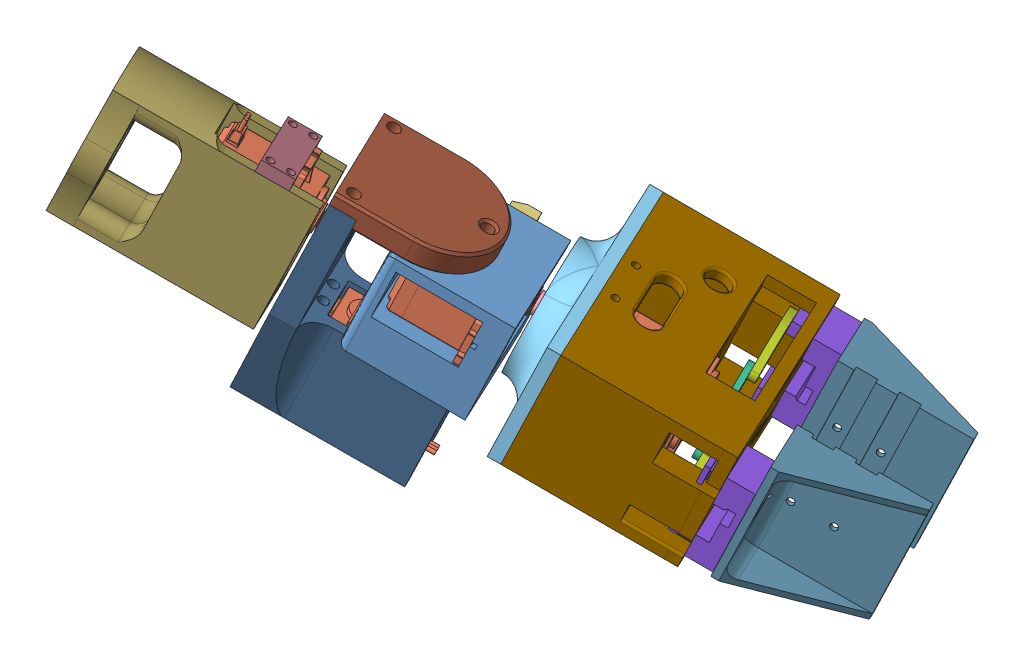
SolidWorks assembly Assem1_Arm_V2, configuration Default. Lengths in mm.
Overall size (291.27 151.15 200.95).
25 component instances, 16 part files, 64 mates.
Components (placement in the parent):
- Gripper_Servo_Case_01-1: Gripper_Servo_Case_01 [Default] at (637.8527 1736.4964 358.4688) x (-0.339499 -0.919036 0.200284) z (0.832449 -0.392704 -0.390912) size (42 54.23 47.25)
- servoMotorMG996R-1: servoMotorMG996R [Default] at (649.6883 1708.0671 323.7215) x (-0.437915 -0.034012 -0.898373) z (-0.339499 -0.919036 0.200284) size (56.95 44.55 19.7)
- Gripper_Case_Cover-1: Gripper_Case_Cover [Default] at (642.9248 1721.1114 296.4702) x (-0.339499 -0.919036 0.200284) z (0.832449 -0.392704 -0.390912) size (30 10 10)
- servoMotorMG996R_Part_Connection_02-3: servoMotorMG996R_Part_Connection_02 [Default] at (660.7487 1700.4192 307.3765) x (-0.339908 -0.919067 0.199444) z (-0.437597 -0.033153 -0.89856) size (20.7 5.75 20.7)
- Base-1: Base [Default] at (676.3768 1700.3789 299.7672) x (0.437597 0.033153 0.89856) z (-0.339908 -0.919067 0.199444) size (100 16.72 50)
- servoMotorMG996R-3: servoMotorMG996R [Default] at (703.1283 1682.8468 298.6268) x (-0.437597 -0.033153 -0.89856) z (-0.339908 -0.919067 0.199444) size (56.95 44.55 19.7)
- Steel_Bar_01-1: Steel_Bar_01 [Default] at (778.4176 1569.0185 297.1188) x (-0.8415 0.403515 0.359239) z (-0.523541 -0.444939 -0.726591) size (40 200 40) (hidden)
- servoMotorMG996R_Part_Connection_04-1: servoMotorMG996R_Part_Connection_04 [Default] at (714.1921 1675.2077 282.2804) x (0.530416 0.768818 0.35718) z (0.160274 -0.50468 0.848298) size (12.1 5.75 37.4)
- Part4-1: Part4 [Default] at (707.8264 1685.09 258.7968) x (-0.312756 0.249358 -0.916517) z (0.832449 -0.392704 -0.390912) size (31.74 9.94 3)
- Part4-3: Part4 [Default] at (724.4217 1663.1396 308.5134) x (-0.326632 0.222103 -0.918685) z (-0.832449 0.392704 0.390912) size (31.74 9.94 3)
- Part3-1: Part3 [Default] at (712.8244 1667.3969 230.1682) x (-0.339908 -0.919067 0.199444) z (0.437597 0.033153 0.89856) size (35.5 19.25 20)
- Part3-2: Part3 [Default] at (752.6871 1665.5038 316.9578) x (0.339908 0.919067 -0.199444) z (-0.437597 -0.033153 -0.89856) size (35.5 19.25 20)
- Rack_Pinion_Base-1: Rack_Pinion_Base [Default] at (693.6373 1645.9394 237.7253) x (0.437597 0.033153 0.89856) z (-0.832449 0.392704 0.390912) size (100 50 65.35)
- servoMotorMG996R-6: servoMotorMG996R [Default] at (617.9256 1679.4163 340.3753) x (0.829062 -0.392954 -0.397799) z (0.444294 0.030996 0.895345) size (56.95 44.55 19.7)
- servoMotorMG996R_Part_Connection_02-1: servoMotorMG996R_Part_Connection_02 [Default] at (632.6138 1692.5415 332.6323) x (0.832449 -0.392704 -0.390912) z (-0.437915 -0.034012 -0.898373) size (20.7 5.75 20.7)
- Servo_Case_02-1: Servo_Case_02 [Default] at (599.422 1669.5924 361.7923) x (0.339499 0.919036 -0.200284) z (-0.829062 0.392954 0.397799) size (91.25 57 64)
- KUKA_GRIPPER_SERVO_Case_02-1: KUKA_GRIPPER_SERVO_Case_02 [Default] at (619.1522 1750.2604 365.9623) x (0.829062 -0.392954 -0.397799) z (0.339499 0.919036 -0.200284) size (54 50 9.8) (hidden)
- KUKA_GRIPPER_SERVO_Case_02_Connector-1: KUKA_GRIPPER_SERVO_Case_02_Connector [Default] at (643.6987 1721.787 326.8452) x (0.074993 0.185806 0.97972) z (-0.937612 0.347634 0.00584) size (10 17 10) (hidden)
- KUKA_GRIPPER_SERVO_Case_02-2: KUKA_GRIPPER_SERVO_Case_02 [Default] at (619.1522 1750.2604 365.9623) x (0.829062 -0.392954 -0.397799) z (0.339499 0.919036 -0.200284) size (54 50 9.8)
- servoMotorMG996R-7: servoMotorMG996R [Default] at (584.9214 1721.7159 357.0059) x (0.299141 0.912756 -0.278192) z (-0.47241 -0.11164 -0.87428) size (56.95 44.55 19.7)
- KUKA_GRIPPER_FLANGE-1: KUKA_GRIPPER_FLANGE [Default] at (528.7604 1726.7228 397.4072) x (-0.47241 -0.11164 -0.87428) z (0.829062 -0.392954 -0.397799) size (40 60 76)
- servoMotorMG996R_Part_Connection_02-2: servoMotorMG996R_Part_Connection_02 [Default] at (603.3632 1723.6258 346.7971) x (-0.339499 -0.919036 0.200284) z (-0.444294 -0.030996 -0.895345) size (20.7 5.75 20.7)
- KUKA_GRIPPER_SERVO_Case-1: KUKA_GRIPPER_SERVO_Case [Default] at (584.2622 1740.5162 337.0609) x (-0.829062 0.392954 0.397799) z (-0.47241 -0.11164 -0.87428) size (12.5 7 30)
- Part2-1: Part2 [Default] at (709.9559 1642.3901 249.1812) x (0.437597 0.033153 0.89856) z (0.339908 0.919067 -0.199444) size (26 50 50)
- Part2-2: Part2 [Default] at (755.5556 1690.5106 297.9448) x (-0.437597 -0.033153 -0.89856) z (-0.339908 -0.919067 0.199444) size (26 50 50)
Mates (geometry in assembly coordinates):
- Coincident91: coincident anti-aligned: plane of Gripper_Servo_Case_01-1 through (648.3749 1698.2317 295.3648) normal (0.425622 0.904876 -0.006807); plane of servoMotorMG996R-1 through (622.1194 1710.7221 314.0836) normal (-0.425622 -0.904876 0.006807)
- Concentric344: concentric aligned: cylinder of servoMotorMG996R_Part_Connection_02-1 through (630.2193 1691.1659 329.0007) axis (0.425622 0.904876 -0.006807) radius 1.5; cylinder of servoMotorMG996R-6 through (611.2579 1650.8537 329.3039) axis (0.425622 0.904876 -0.006807) radius 1.2
- Coincident2520: coincident anti-aligned: plane of servoMotorMG996R_Part_Connection_02-1 through (631.2195 1693.2923 328.9847) normal (0.425622 0.904876 -0.006807); plane of Gripper_Servo_Case_01-1 through (631.2195 1693.2923 328.9847) normal (-0.425622 -0.904876 0.006807)
- Concentric354: concentric aligned: cylinder of servoMotorMG996R_Part_Connection_02-1 through (630.2193 1691.1659 329.0007) axis (0.425622 0.904876 -0.006807) radius 1.5; cylinder of Gripper_Servo_Case_01-1 through (631.6452 1694.1972 328.9779) axis (0.425622 0.904876 -0.006807) radius 3.5
- Concentric355: concentric anti-aligned: cylinder of servoMotorMG996R_Part_Connection_02-1 through (632.3865 1690.1961 335.5858) axis (0.425622 0.904876 -0.006807) radius 0.75; cylinder of Gripper_Servo_Case_01-1 through (637.6429 1701.3713 335.5017) axis (-0.425622 -0.904876 0.006807) radius 1
- Concentric356: concentric aligned: cylinder of servoMotorMG996R_Part_Connection_02-1 through (630.2193 1691.1659 329.0007) axis (0.425622 0.904876 -0.006807) radius 1.5; cylinder of servoMotorMG996R-6 through (611.2579 1650.8537 329.3039) axis (0.425622 0.904876 -0.006807) radius 1.2
- Coincident2523: coincident anti-aligned: plane of servoMotorMG996R_Part_Connection_02-1 through (630.2193 1691.1659 329.0007) normal (-0.425622 -0.904876 0.006807); plane of servoMotorMG996R-6 through (630.2193 1691.1659 329.0007) normal (0.425622 0.904876 -0.006807)
- Coincident2553: coincident anti-aligned: plane of Servo_Case_02-1 through (603.2766 1724.0263 346.2209) normal (-0.829062 0.392954 0.397799); plane of servoMotorMG996R_Part_Connection_02-2 through (603.2766 1724.0263 346.2209) normal (0.829062 -0.392954 -0.397799)
- Concentric365: concentric aligned: cylinder of servoMotorMG996R-7 through (564.3936 1742.4559 364.8776) axis (0.829062 -0.392954 -0.397799) radius 1.2; cylinder of servoMotorMG996R_Part_Connection_02-2 through (601.3283 1724.9498 347.1557) axis (0.829062 -0.392954 -0.397799) radius 1.5
- Coincident2554: coincident anti-aligned: plane of servoMotorMG996R-7 through (601.3283 1724.9498 347.1557) normal (0.829062 -0.392954 -0.397799); plane of servoMotorMG996R_Part_Connection_02-2 through (601.3283 1724.9498 347.1557) normal (-0.829062 0.392954 0.397799)
- Coincident2555: coincident anti-aligned: plane of Base-1 through (663.0713 1702.3078 309.0934) normal (-0.850292 0.402498 0.339115); plane of servoMotorMG996R_Part_Connection_02-3 through (663.0713 1702.3078 309.0934) normal (0.850292 -0.402498 -0.339115)
- Concentric366: concentric anti-aligned: cylinder of Base-1 through (674.3475 1704.6783 305.0652) axis (-0.850292 0.402498 0.339115) radius 1; cylinder of servoMotorMG996R_Part_Connection_02-3 through (663.8464 1709.6492 309.2532) axis (0.850292 -0.402498 -0.339115) radius 0.75
- Concentric367: concentric anti-aligned: cylinder of Base-1 through (668.8009 1691.8872 306.3394) axis (-0.850292 0.402498 0.339115) radius 1; cylinder of servoMotorMG996R_Part_Connection_02-3 through (658.2998 1696.8581 310.5275) axis (0.850292 -0.402498 -0.339115) radius 0.75
- Concentric369: concentric aligned: cylinder of servoMotorMG996R-1 through (623.1926 1721.1849 324.9979) axis (0.850292 -0.402498 -0.339115) radius 1.2; cylinder of servoMotorMG996R_Part_Connection_02-3 through (661.0731 1703.2536 309.8904) axis (0.850292 -0.402498 -0.339115) radius 1.5
- Coincident2556: coincident anti-aligned: plane of servoMotorMG996R-1 through (661.0731 1703.2536 309.8904) normal (0.850292 -0.402498 -0.339115); plane of servoMotorMG996R_Part_Connection_02-3 through (661.0731 1703.2536 309.8904) normal (-0.850292 0.402498 0.339115)
- Coincident2557: coincident aligned: plane of Gripper_Servo_Case_01-1 through (640.0214 1730.2769 360.2364) normal (0.309597 -0.138547 0.94072); plane of servoMotorMG996R-1 through (659.1546 1700.227 349.5139) normal (0.309597 -0.138547 0.94072)
- Coincident2558: coincident anti-aligned: plane of Gripper_Servo_Case_01-1 through (663.7675 1714.0178 344.7117) normal (-0.850292 0.402498 0.339115); plane of servoMotorMG996R-1 through (663.4856 1709.6256 349.2181) normal (0.850292 -0.402498 -0.339115)
- Coincident2561: coincident anti-aligned: plane of servoMotorMG996R-6 through (591.3986 1694.1858 337.7717) normal (0.425622 0.904876 -0.006807); plane of Servo_Case_02-1 through (603.2318 1688.7182 350.8395) normal (-0.425622 -0.904876 0.006807)
- Coincident2562: coincident aligned: plane of servoMotorMG996R-6 through (639.7227 1671.3664 325.8814) normal (0.829062 -0.392954 -0.397799); plane of Servo_Case_02-1 through (632.834 1650.3421 332.2927) normal (0.829062 -0.392954 -0.397799)
- Coincident2563: coincident anti-aligned: plane of servoMotorMG996R-6 through (586.3323 1670.3331 331.8948) normal (-0.362633 0.163669 -0.917447); plane of Servo_Case_02-1 through (620.7182 1643.7437 313.5599) normal (0.362633 -0.163669 0.917447)
- Coincident2581: coincident anti-aligned: plane of servoMotorMG996R-7 through (581.9018 1697.476 368.6242) normal (0.829062 -0.392954 -0.397799); plane of KUKA_GRIPPER_FLANGE-1 through (579.6137 1685.4078 375.7766) normal (-0.829062 0.392954 0.397799)
- Coincident2586: coincident anti-aligned: plane of KUKA_GRIPPER_FLANGE-1 through (607.8859 1739.3858 358.7544) normal (0.299141 0.912756 -0.278192); plane of KUKA_GRIPPER_SERVO_Case-1 through (584.2622 1740.5162 337.0609) normal (-0.299141 -0.912756 0.278192)
- Concentric406: concentric aligned: cylinder of servoMotorMG996R-7 through (564.3936 1742.4559 364.8776) axis (0.829062 -0.392954 -0.397799) radius 1.2; cylinder of Servo_Case_02-1 through (604.1056 1723.6334 345.8231) axis (0.829062 -0.392954 -0.397799) radius 3.5
- Concentric407: concentric anti-aligned: cylinder of Servo_Case_02-1 through (614.5466 1726.4309 342.1952) axis (-0.829062 0.392954 0.397799) radius 1; cylinder of servoMotorMG996R_Part_Connection_02-2 through (604.3076 1731.2839 347.108) axis (0.829062 -0.392954 -0.397799) radius 0.75
- Concentric408: concentric anti-aligned: cylinder of Servo_Case_02-1 through (608.5879 1713.7627 342.2905) axis (-0.829062 0.392954 0.397799) radius 1; cylinder of servoMotorMG996R_Part_Connection_02-2 through (598.3489 1718.6157 347.2033) axis (0.829062 -0.392954 -0.397799) radius 0.75
- Concentric411: concentric anti-aligned: cylinder of Servo_Case_02-1 through (604.962 1746.3021 327.729) axis (0.425622 0.904876 -0.006807) radius 2.6; cylinder of KUKA_GRIPPER_SERVO_Case_02-1 through (609.2182 1755.3509 327.6609) axis (-0.425622 -0.904876 0.006807) radius 2.6
- Concentric412: concentric anti-aligned: cylinder of Servo_Case_02-1 through (619.4673 1739.7553 364.4269) axis (0.425622 0.904876 -0.006807) radius 2.6; cylinder of KUKA_GRIPPER_SERVO_Case_02-1 through (623.7235 1748.8041 364.3588) axis (-0.425622 -0.904876 0.006807) radius 2.6
- Coincident2592: coincident aligned: circle of Servo_Case_02-1; circle of KUKA_GRIPPER_SERVO_Case_02-1
- Concentric415: concentric aligned: cylinder of KUKA_GRIPPER_SERVO_Case_02-1 through (651.4595 1735.7151 329.2611) axis (-0.425622 -0.904876 0.006807) radius 2.6; cylinder of KUKA_GRIPPER_SERVO_Case_02_Connector-1 through (651.3744 1735.5341 329.2625) axis (-0.425622 -0.904876 0.006807) radius 2.6
- Coincident2593: coincident anti-aligned: plane of KUKA_GRIPPER_SERVO_Case_02-1 through (621.3914 1749.9505 370.935) normal (0.425622 0.904876 -0.006807); plane of KUKA_GRIPPER_SERVO_Case_02_Connector-1 through (651.3744 1735.5341 329.2625) normal (-0.425622 -0.904876 0.006807)
- Coincident2643: coincident anti-aligned: circle of Base-1; circle of Rack_Pinion_Base-1
- Coincident2644: coincident anti-aligned: circle of Base-1; circle of Rack_Pinion_Base-1
- Concentric432: concentric anti-aligned: cylinder of servoMotorMG996R-3 through (677.7815 1695.3445 303.2272) axis (0.850292 -0.402498 -0.339115) radius 1.2; cylinder of Rack_Pinion_Base-1 through (731.9451 1669.7054 281.6255) axis (-0.850292 0.402498 0.339115) radius 5
- Parallel13: parallel aligned: plane of servoMotorMG996R-3 through (712.8369 1671.8751 328.4508) normal (-0.396188 -0.913647 0.091019); plane of Rack_Pinion_Base-1 through (735.2189 1658.0912 333.1077) normal (-0.396188 -0.913647 0.091019)
- Coincident2674: coincident anti-aligned: plane of servoMotorMG996R-7 through (579.912 1698.4191 369.5789) normal (-0.829062 0.392954 0.397799); plane of KUKA_GRIPPER_SERVO_Case-1 through (585.758 1745.08 335.6699) normal (0.829062 -0.392954 -0.397799)
- Coincident2678: coincident aligned: plane of KUKA_GRIPPER_FLANGE-1 through (551.7621 1742.473 354.3723) normal (-0.47241 -0.11164 -0.87428); plane of KUKA_GRIPPER_SERVO_Case-1 through (585.758 1745.08 335.6699) normal (-0.47241 -0.11164 -0.87428)
- Concentric449: concentric aligned: circle of KUKA_GRIPPER_FLANGE-1; circle of KUKA_GRIPPER_SERVO_Case-1
- Coincident2680: coincident aligned: circle of Gripper_Servo_Case_01-1; cylinder of Gripper_Case_Cover-1 through (645.197 1724.6288 300.2984) axis (-0.309597 0.138547 -0.94072) radius 1.5
- Coincident2681: coincident aligned: circle of Gripper_Servo_Case_01-1; cylinder of Gripper_Case_Cover-1 through (634.5565 1702.007 300.4686) axis (-0.309597 0.138547 -0.94072) radius 1.5
- Coincident2682: coincident anti-aligned: plane of Gripper_Servo_Case_01-1 through (623.3032 1737.7585 309.4375) normal (-0.309597 0.138547 -0.94072); plane of Gripper_Case_Cover-1 through (648.3868 1725.8848 299.4336) normal (0.309597 -0.138547 0.94072)
- Coincident2690: coincident anti-aligned: plane of servoMotorMG996R-3 through (719.2415 1686.8498 326.7361) normal (0.850292 -0.402498 -0.339115); plane of Rack_Pinion_Base-1 through (718.1293 1656.1765 360.3537) normal (-0.850292 0.402498 0.339115)
- Concentric451: concentric aligned: cylinder of servoMotorMG996R-3 through (677.7815 1695.3445 303.2272) axis (0.850292 -0.402498 -0.339115) radius 1.2; cylinder of servoMotorMG996R_Part_Connection_04-1 through (715.662 1677.4132 288.1196) axis (0.850292 -0.402498 -0.339115) radius 1.5
- Concentric454: concentric anti-aligned: cylinder of servoMotorMG996R_Part_Connection_04-1 through (686.6273 1707.4558 295.5761) axis (0.850292 -0.402498 -0.339115) radius 0.75; cylinder of Part4-1 through (724.6002 1689.4808 280.4316) axis (-0.850292 0.402498 0.339115) radius 1.5
- Coincident2692: coincident anti-aligned: plane of servoMotorMG996R_Part_Connection_04-1 through (717.6602 1676.4673 287.3227) normal (0.850292 -0.402498 -0.339115); plane of Part4-1 through (711.5956 1683.5827 263.6712) normal (-0.850292 0.402498 0.339115)
- Concentric457: concentric aligned: cylinder of servoMotorMG996R_Part_Connection_04-1 through (677.849 1679.0139 307.3234) axis (0.850292 -0.402498 -0.339115) radius 0.75; cylinder of Part4-3 through (713.271 1662.2464 293.1963) axis (0.850292 -0.402498 -0.339115) radius 1.5
- Coincident2697: coincident anti-aligned: plane of Rack_Pinion_Base-1 through (711.6653 1689.3695 236.9254) normal (0.396188 0.913647 -0.091019); plane of Part3-1 through (726.1398 1685.6763 262.8579) normal (-0.396188 -0.913647 0.091019)
- Coincident2698: coincident anti-aligned: plane of Rack_Pinion_Base-1 through (734.4286 1687.2499 281.7734) normal (0.850292 -0.402498 -0.339115); plane of Part3-1 through (728.3189 1690.7013 262.3573) normal (-0.850292 0.402498 0.339115)
- Coincident2699: coincident anti-aligned: plane of servoMotorMG996R-3 through (715.662 1677.4132 288.1196) normal (0.850292 -0.402498 -0.339115); plane of servoMotorMG996R_Part_Connection_04-1 through (715.662 1677.4132 288.1196) normal (-0.850292 0.402498 0.339115)
- Coincident2700: coincident anti-aligned: plane of servoMotorMG996R_Part_Connection_04-1 through (717.6602 1676.4673 287.3227) normal (0.850292 -0.402498 -0.339115); plane of Part4-3 through (719.5657 1670.7618 298.8726) normal (-0.850292 0.402498 0.339115)
- Concentric460: concentric aligned: cylinder of Part4-1 through (716.2821 1692.3004 256.2285) axis (-0.850292 0.402498 0.339115) radius 1.5; cylinder of Part3-1 through (724.8276 1688.2553 252.8204) axis (-0.850292 0.402498 0.339115) radius 0.875
- Coincident2701: coincident anti-aligned: plane of Rack_Pinion_Base-1 through (734.4286 1687.2499 281.7734) normal (0.850292 -0.402498 -0.339115); plane of Part3-2 through (735.6854 1672.6062 302.3052) normal (-0.850292 0.402498 0.339115)
- Concentric461: concentric anti-aligned: cylinder of Part4-3 through (721.589 1659.4268 317.3995) axis (0.850292 -0.402498 -0.339115) radius 1.5; cylinder of Part3-2 through (732.6854 1654.1742 312.974) axis (-0.850292 0.402498 0.339115) radius 0.875
- Coincident2703: coincident anti-aligned: plane of Rack_Pinion_Base-1 through (735.2189 1658.0912 333.1077) normal (-0.396188 -0.913647 0.091019); plane of Part3-2 through (729.2473 1657.7595 303.7843) normal (0.396188 0.913647 -0.091019)
- Coincident2704: coincident anti-aligned: circle of Servo_Case_02-1; cylinder of KUKA_GRIPPER_SERVO_Case_02-2 through (609.2182 1755.3509 327.6609) axis (-0.425622 -0.904876 0.006807) radius 2.6
- Coincident2705: coincident anti-aligned: circle of Servo_Case_02-1; cylinder of KUKA_GRIPPER_SERVO_Case_02-2 through (623.7235 1748.8041 364.3588) axis (-0.425622 -0.904876 0.006807) radius 2.6
- Coincident2706: coincident anti-aligned: plane of Servo_Case_02-1 through (619.2633 1745.4262 370.9691) normal (0.425622 0.904876 -0.006807); plane of KUKA_GRIPPER_SERVO_Case_02-2 through (619.2633 1745.4262 370.9691) normal (-0.425622 -0.904876 0.006807)
- Concentric463: concentric anti-aligned: cylinder of Part3-1 through (728.533 1667.5211 244.848) axis (-0.850292 0.402498 0.339115) radius 1.75; cylinder of Part2-1 through (708.9248 1676.8029 252.6682) axis (0.850292 -0.402498 -0.339115) radius 1
- Parallel16: parallel aligned: plane of Part3-1 through (730.6108 1671.1715 260.3212) normal (0.346466 -0.056961 0.936331); plane of Part2-1 through (742.1977 1691.0445 265.7867) normal (0.346466 -0.056961 0.936331)
- Coincident2711: coincident anti-aligned: plane of Part3-1 through (737.2469 1686.4751 258.7966) normal (0.850292 -0.402498 -0.339115); plane of Part2-1 through (733.1896 1692.5254 241.4421) normal (-0.850292 0.402498 0.339115)
- Concentric464: concentric anti-aligned: cylinder of Part3-2 through (753.1278 1663.4776 311.3157) axis (-0.850292 0.402498 0.339115) radius 1.75; cylinder of Part2-2 through (733.5196 1672.7594 319.1359) axis (0.850292 -0.402498 -0.339115) radius 1
- Parallel17: parallel aligned: plane of Part3-2 through (742.6325 1663.8118 299.1996) normal (-0.346466 0.056961 -0.936331); plane of Part2-2 through (731.0456 1643.9388 293.7341) normal (-0.346466 0.056961 -0.936331)
- Coincident2714: coincident anti-aligned: plane of Part3-2 through (735.9964 1648.5082 300.7242) normal (0.850292 -0.402498 -0.339115); plane of Part2-2 through (740.0537 1642.4578 318.0787) normal (-0.850292 0.402498 0.339115)
- Coincident2715: coincident anti-aligned: plane of servoMotorMG996R-7 through (566.0705 1714.0155 378.8696) normal (0.47241 0.11164 0.87428); plane of KUKA_GRIPPER_FLANGE-1 through (604.4139 1734.776 356.072) normal (-0.47241 -0.11164 -0.87428)
- Coincident2717: coincident anti-aligned: line of servoMotorMG996R-7 through (580.6322 1702.9108 360.6096) axis (-0.47241 -0.11164 -0.87428); line of KUKA_GRIPPER_FLANGE-1 through (575.6759 1701.3185 351.8529) axis (0.47241 0.11164 0.87428)
